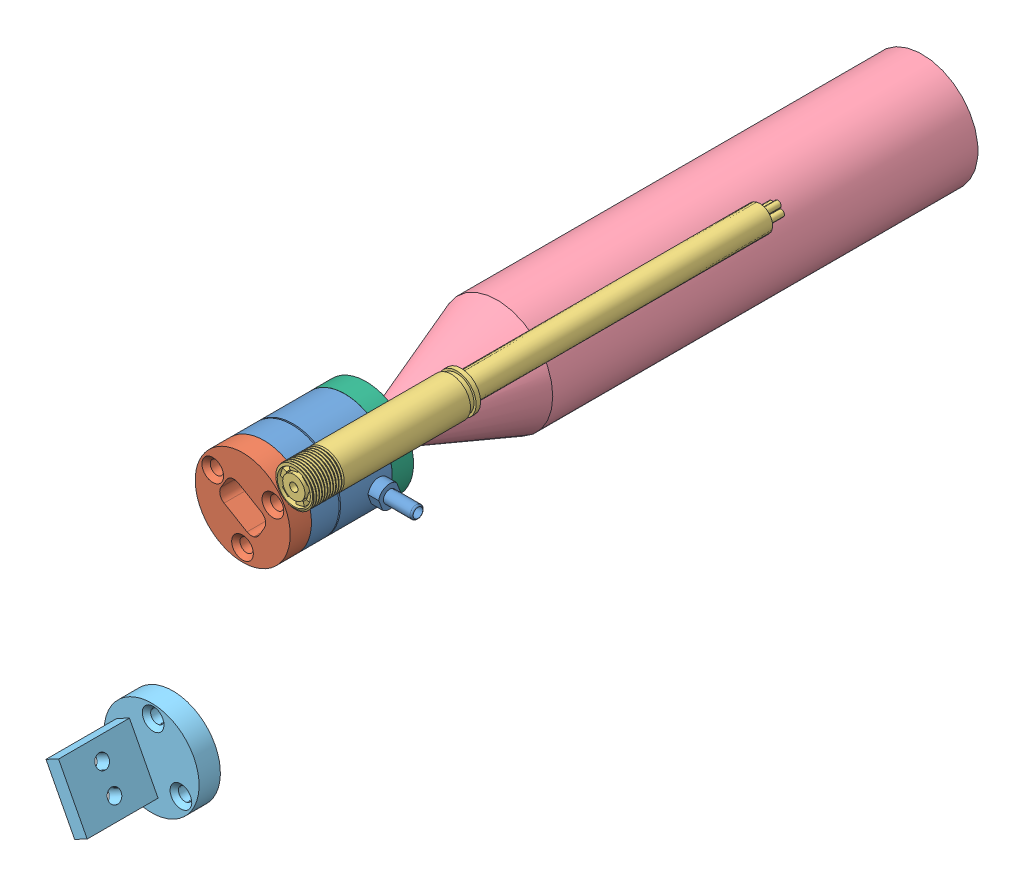
SolidWorks assembly Assem1, configuration Default. Lengths in mm.
Overall size (43.28 70.7 134.31).
6 component instances, 6 part files, 7 mates.
Components (placement in the parent):
- ATI-9105-TW-Nano17-R-1: ATI-9105-TW-Nano17-R [Default] at (8.2872 14.7073 22.6599) size (23.98 16.99 14.48)
- Forecep Affector-1: Forecep Affector [Default] at (8.2872 14.7073 22.6599) x (0.862677 -0.505755 0) z (0 0 1) size (17.02 17.02 3.81)
- 7mm endoscope-1: 7mm endoscope [Default] at (17.445 22.4252 26.4699) x (0 0 -1) z (-0.283212 -0.959057 0) size (86.7 8.04 6.96)
- Estimated-MiscrosribeMX-StylusSLDPRT-1: Estimated-MiscrosribeMX-StylusSLDPRT [Default] at (8.4399 14.3272 -95.1369) size (20 20 95.25)
- Scalpel Affector-1: Scalpel Affector [Default] at (-8.0375 -32.3187 22.6599) x (0.887032 0.461708 0) z (0 0 1) size (17.02 17.02 16.51)
- Microscribe-To-Nano17-Mount-1: Microscribe-To-Nano17-Mount [Default] at (8.2872 14.7073 4.3719) x (0.997542 0.070064 0) z (0 0 1) size (17.02 17.02 10.16)
Mates (geometry in assembly coordinates):
- Coincident2: coincident anti-aligned: plane of ATI-9105-TW-Nano17-R-1 through (8.2872 14.7073 22.6599) normal (0 0 1); plane of Forecep Affector-1 through (8.2872 14.7073 22.6599) normal (0 0 -1)
- Concentric1: concentric anti-aligned: cylinder of ATI-9105-TW-Nano17-R-1 through (8.2872 14.7073 17.7069) axis (0 0 1) radius 8.4963; cylinder of Forecep Affector-1 through (8.2872 14.7073 26.4699) axis (0 0 -1) radius 8.509
- Coincident3: coincident aligned: circle of Forecep Affector-1; plane of 7mm endoscope-1 through (17.445 22.4252 26.4699) normal (0 0 1)
- Tangent3: tangent: curve of 7mm endoscope-1; cylinder of ATI-9105-TW-Nano17-R-1 through (8.2872 14.7073 17.7069) axis (0 0 1) radius 8.4963
- Coincident5: coincident anti-aligned: plane of ATI-9105-TW-Nano17-R-1 through (8.2872 14.7073 22.6599) normal (0 0 1); plane of Scalpel Affector-1 through (-8.0375 -32.3187 22.6599) normal (0 0 -1)
- Concentric3: concentric aligned: circle of ATI-9105-TW-Nano17-R-1; circle of Microscribe-To-Nano17-Mount-1
- Coincident7: coincident anti-aligned: plane of ATI-9105-TW-Nano17-R-1 through (8.2872 14.7073 8.1819) normal (0 0 -1); plane of Microscribe-To-Nano17-Mount-1 through (8.2872 14.7073 8.1819) normal (0 0 1)
